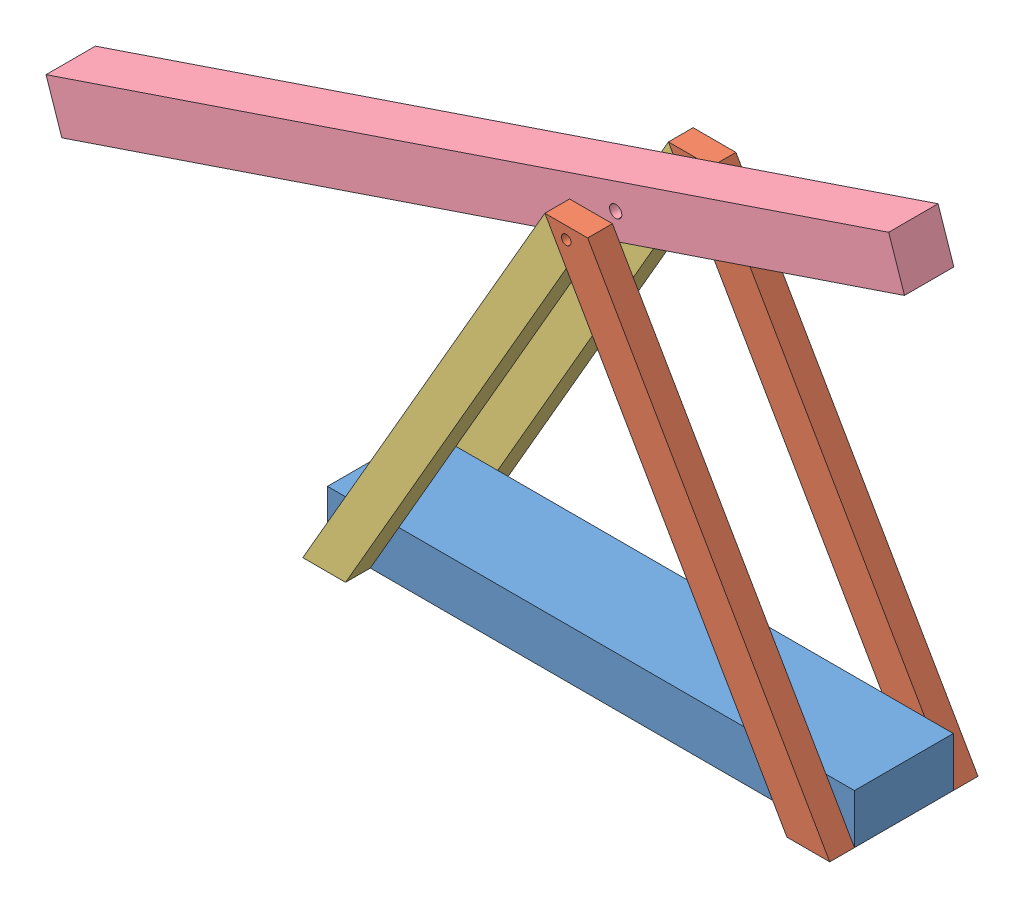
SolidWorks assembly trebuchet, configuration Default. Lengths in mm.
Overall size (882.52 559.06 152.4).
6 component instances, 4 part files, 14 mates.
Components (placement in the parent):
- trebuchetbase-1: trebuchetbase [Default] at origin size (541.73 50.8 101.6)
- trebuchetside-1: trebuchetside [Default] at (124.4341 215.5261 50.8) x (0.5 -0.866025 0) z (0 0 1) size (519.73 38.1 25.4)
- trebuchetside-2: trebuchetside [Default] at (124.4341 215.5261 -76.2) x (0.5 -0.866025 0) z (0 0 1) size (519.73 38.1 25.4)
- trebuchetside2-1: trebuchetside2 [Default] at (-135.4326 196.4761 50.8) x (0.5 0.866025 0) z (0 0 1) size (497.74 38.1 25.4)
- trebuchetside2-2: trebuchetside2 [Default] at (-135.4326 196.4761 -76.2) x (0.5 0.866025 0) z (0 0 1) size (497.74 38.1 25.4)
- trebuchetbeam-1: trebuchetbeam [Default] at (-136.2429 345.4909 0) x (0.947349 0.320202 0) z (0 0 1) size (914.4 50.8 50.8)
Mates (geometry in assembly coordinates):
- Coincident2: coincident aligned: line of trebuchetbase-1 through (-270.8652 0 50.8) axis (1 0 0); line of trebuchetside-1 through (226.8711 0 50.8) axis (1 0 0)
- Coincident3: coincident: point of trebuchetbase-1; point of trebuchetside-1
- Coincident4: coincident anti-aligned: plane of trebuchetbase-1 through (-270.8652 50.8 50.8) normal (0 0 1); plane of trebuchetside-1 through (124.4341 215.5261 50.8) normal (0 0 -1)
- Coincident7: coincident anti-aligned: line of trebuchetbase-1 through (270.8652 0 -50.8) axis (-1 0 0); line of trebuchetside-2 through (226.8711 0 -50.8) axis (1 0 0)
- Coincident8: coincident: point of trebuchetbase-1; point of trebuchetside-2
- Coincident9: coincident anti-aligned: plane of trebuchetbase-1 through (-270.8652 50.8 -50.8) normal (0 0 -1); plane of trebuchetside-2 through (124.4341 215.5261 -50.8) normal (0 0 1)
- Coincident10: coincident aligned: line of trebuchetbase-1 through (-270.8652 0 50.8) axis (1 0 0); line of trebuchetside2-1 through (-270.8652 0 50.8) axis (1 0 0)
- Coincident11: coincident: point of trebuchetbase-1; point of trebuchetside2-1
- Coincident12: coincident anti-aligned: plane of trebuchetbase-1 through (-270.8652 50.8 50.8) normal (0 0 1); plane of trebuchetside2-1 through (-135.4326 196.4761 50.8) normal (0 0 -1)
- Coincident13: coincident anti-aligned: line of trebuchetbase-1 through (270.8652 0 -50.8) axis (-1 0 0); line of trebuchetside2-2 through (-270.8652 0 -50.8) axis (1 0 0)
- Coincident14: coincident: point of trebuchetbase-1; point of trebuchetside2-2
- Coincident15: coincident anti-aligned: plane of trebuchetbase-1 through (-270.8652 50.8 -50.8) normal (0 0 -1); plane of trebuchetside2-2 through (-135.4326 196.4761 -50.8) normal (0 0 1)
- Concentric1: concentric aligned: cylinder of trebuchetside-1 through (0 418.3523 76.2) axis (0 0 -1) radius 4.9595; cylinder of trebuchetbeam-1 through (0 418.3523 25.4) axis (0 0 -1) radius 6.35
- Distance1: distance = 25.4 mm anti-aligned: plane of trebuchetside-2 through (124.4341 215.5261 -50.8) normal (0 0 1); plane of trebuchetbeam-1 through (-585.6373 247.2199 -25.4) normal (0 0 -1)
